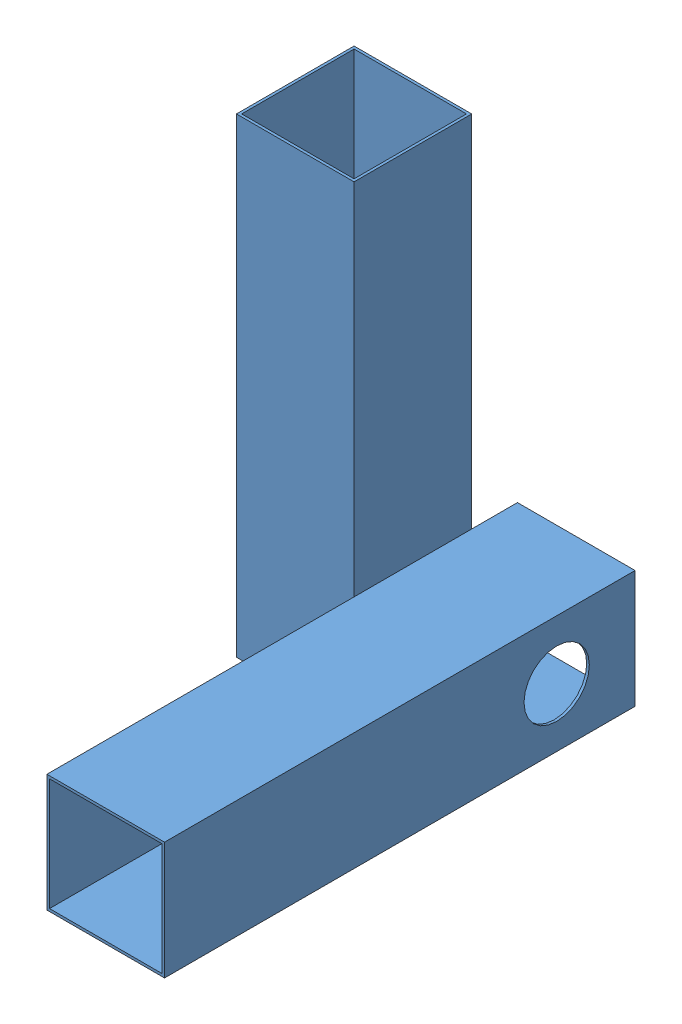
SolidWorks assembly Assem1, configuration Default. Lengths in mm.
Overall size (100 180 180).
2 component instances, 1 part files, 6 mates.
Components (placement in the parent):
- Part1-1: Part1 [Default] at (22.5 -180 22.5) x (1 0 0) z (0 1 0) size (45 45 180)
- Part1-2: Part1 [Default] at (77.5 -150 -7.5) size (45 45 180)
Mates (geometry in assembly coordinates):
- Concentric1: concentric: cylinder of Part1-1 through (-135 -150 22.5) axis (1 0 0) radius 12.5; cylinder of Part1-2 through (-80 -150 22.5) axis (1 0 0) radius 12.5
- Distance1: distance = 10 mm: plane of Part1-2 through (55 -172.5 172.5) normal (-1 0 0); plane of Part1-1 through (45 0 45) normal (1 0 0)
- Coincident2: coincident: plane of Part1-1 through (0 0 0) normal (0 0 -1); plane of assembly
- Coincident3: coincident: plane of Part1-1 through (22.5 0 22.5) normal (0 1 0); plane of assembly
- Coincident4: coincident: plane of Part1-1 through (0 0 45) normal (-1 0 0); plane of assembly
- Parallel2: parallel: plane of Part1-1 through (22.5 0 22.5) normal (0 1 0); plane of Part1-2 through (55 -127.5 172.5) normal (0 1 0)
